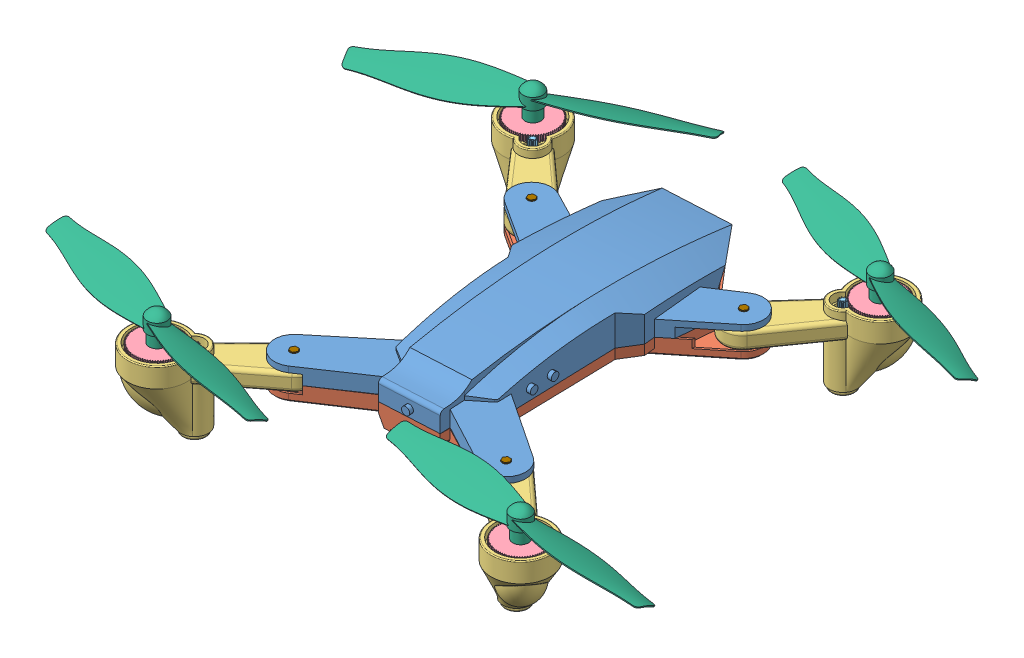
SolidWorks assembly FINALassembly, configuration Default. Lengths in mm.
Overall size (324.66 53.5 263.81).
30 component instances, 14 part files, 79 mates.
Components (placement in the parent):
- FINALtop-1: FINALtop [Default] at (85.5252 115.5284 181.2503) x (0.998665 0 -0.051658) z (0.051658 0 0.998665) size (123 19.95 170)
- FINALlower body-2: FINALlower body [Default] at (85.5252 110.5284 181.2503) x (0.998665 0 -0.051658) z (0.051658 0 0.998665) size (123 15 167)
- FINALstand-5: FINALstand [Default] at (179.7439 114.5284 292.0925) x (0.777982 0 0.628286) z (-0.628286 0 0.777982) size (75.23 38.54 30.33)
- FINALstand-6: FINALstand [Default] at (-2.951 114.5284 103.1371) x (-0.700616 0 -0.713538) z (0.713538 0 -0.700616) size (75.23 38.54 30.33)
- FINALstand-7: FINALstand [Default] at (0.9617 114.5284 298.7646) x (-0.75513 0 0.655575) z (-0.655575 0 -0.75513) size (75.23 38.54 30.33)
- FINALstand-8: FINALstand [Default] at (165.4696 114.5284 94.4251) x (0.623255 0 -0.782019) z (0.782019 0 0.623255) size (75.23 38.54 30.33)
- FINALroter part 1-1: FINALroter part 1 [Default] at (179.7439 104.0284 292.0925) x (0.103425 0 -0.994637) z (0.994637 0 0.103425) size (24 29 23.99)
- FINALroter part 2-1: FINALroter part 2 [Default] at (169.2412 98.5284 283.6107) x (-0.833907 0 0.551904) z (-0.551904 0 -0.833907) size (8 26.1 8)
- FINALroter part 1-2: FINALroter part 1 [Default] at (0.9617 104.5284 298.7646) x (0.963475 0 -0.267798) z (0.267798 0 0.963475) size (24 29 23.99)
- FINALroter part 1-3: FINALroter part 1 [Default] at (-2.951 104.5284 103.1371) x (-0.571485 0 0.820612) z (-0.820612 0 -0.571485) size (24 29 23.99)
- FINALroter part 1-4: FINALroter part 1 [Default] at (165.4696 104.5284 94.4251) x (-0.981624 0 0.190825) z (-0.190825 0 -0.981624) size (24 29 23.99)
- FINALroter part 2-2: FINALroter part 2 [Default] at (157.0556 98.5284 104.9824) x (-0.900487 0 0.434883) z (-0.434883 0 -0.900487) size (8 26.1 8)
- FINALroter part 2-3: FINALroter part 2 [Default] at (6.5073 98.5284 112.7698) x (0.010107 0 0.999949) z (-0.999949 0 0.010107) size (8 26.1 8)
- FINALroter part 2-4: FINALroter part 2 [Default] at (11.156 98.5284 289.9144) x (0.669232 0 0.743054) z (-0.743054 0 0.669232) size (8 26.1 8)
- FINALpropeller-1: FINALpropeller [Default] at (-2.951 124.5284 103.1371) x (0.424928 0 0.905227) z (-0.905227 0 0.424928) size (18.79 15 144.23)
- FINALpropeller-2: FINALpropeller [Default] at (0.9617 124.5284 298.7646) x (-0.249818 0 0.968293) z (-0.968293 0 -0.249818) size (18.79 15 144.23)
- FINALpropeller-3: FINALpropeller [Default] at (179.7439 124.0284 292.0925) x (0.103425 0 -0.994637) z (0.994637 0 0.103425) size (18.79 15 144.23)
- FINALpropeller-4: FINALpropeller [Default] at (165.4696 124.5284 94.4251) x (0.325552 0 -0.945524) z (0.945524 0 0.325552) size (18.79 15 144.23)
- FINALcamera-1: FINALcamera [Default] at (82.4538 106.2974 121.8727) x (0.998665 0 -0.051658) z (0.049898 0.258819 0.964636) size (21 11 14.8)
- FINALbush of gun-2: FINALbush of gun [Default] at (84.398 100.5284 159.46) size (8 2 8)
- FINALbolt-1: FINALbolt [Default] at (141.2182 124.0284 260.9798) x (-0.017216 0 0.999852) z (0.999852 0 0.017216) size (4 12.5 4)
- FINALbolt-2: FINALbolt [Default] at (134.606 124.0284 133.1507) x (-0.017216 0 0.999852) z (0.999852 0 0.017216) size (4 12.5 4)
- FINALbolt-3: FINALbolt [Default] at (31.7435 124.0284 138.4715) x (-0.017216 0 0.999852) z (0.999852 0 0.017216) size (4 12.5 4)
- FINALbolt-4: FINALbolt [Default] at (38.3558 124.0284 266.3006) x (-0.017216 0 0.999852) z (0.999852 0 0.017216) size (4 12.5 4)
- FINALcover-1: FINALcover [Default] at (85.0978 106.5284 159.243) x (0.998665 0 -0.051658) z (-0.051658 0 -0.998665) (suppressed, hidden)
- FINALlower motherboard-2: FINALlower motherboard [Default] at (86.1308 106.5284 150.1776) x (0.998665 0 -0.051658) z (0.051658 0 0.998665) (suppressed, hidden)
- FINALupper cover-1: FINALupper cover [Default] at (85.7105 107.5284 179.7387) x (0.998665 0 -0.051658) z (-0.051658 0 -0.998665) (suppressed, hidden)
- FINALupper motherboard-2: FINALupper motherboard [Default] at (86.2827 104.5284 199.2352) x (0.051658 0 0.998665) z (-0.998665 0 0.051658) (suppressed, hidden)
- FINALupper mb 2-1: FINALupper mb 2 [Default] at (87.6851 104.5284 226.1988) x (0.998665 0 -0.051658) z (0.051658 0 0.998665) (suppressed, hidden)
- FINALgun final-1: FINALgun final [Default] at (85.0965 67.6861 127.2387) x (-0.021673 0 0.999765) z (-0.999765 0 -0.021673) (suppressed, hidden)
Mates (geometry in assembly coordinates):
- Coincident8: coincident anti-aligned: plane of top-1 through (85.5252 115.5284 181.2503) normal (0 -1 0); plane of lower body-2 through (85.5252 115.5284 181.2503) normal (0 1 0)
- Coincident9: coincident aligned: plane of top-1 through (74.5487 134.5284 259.4217) normal (0.051658 0 0.998665); plane of lower body-2 through (74.5487 115.5284 259.4217) normal (0.051658 0 0.998665)
- Coincident12: coincident anti-aligned: plane of top-1 through (85.5252 115.5284 181.2503) normal (0 -1 0); plane of lower body-2 through (85.5252 115.5284 181.2503) normal (0 1 0)
- Width1: width anti-aligned: plane of top-1 through (63.7786 134.5284 239.9521) normal (-0.99742 0 0.071782); plane of lower body-2 through (113.2125 134.5284 237.395) normal (0.999503 0 -0.031513); plane of top-1 through (112.7132 115.5284 237.4208) normal (0.999725 0 -0.023461); plane of lower body-2 through (64.2779 115.5284 239.9263) normal (-0.99681 0 0.079814)
- Concentric2: concentric anti-aligned: cylinder of lower body-2 through (141.2182 112.5284 260.9798) axis (0 -1 0) radius 2; cylinder of stand-5 through (141.2182 110.5284 260.9798) axis (0 1 0) radius 2
- Coincident13: coincident anti-aligned: plane of top-1 through (141.2182 120.5284 260.9798) normal (0 -1 0); plane of stand-5 through (140.8448 120.5284 260.6782) normal (0 1 0)
- Concentric3: concentric anti-aligned: cylinder of lower body-2 through (134.606 112.5284 133.1507) axis (0 -1 0) radius 2; cylinder of stand-8 through (134.606 110.5284 133.1507) axis (0 1 0) radius 2
- Coincident14: coincident anti-aligned: plane of top-1 through (134.606 120.5284 133.1507) normal (0 -1 0); plane of stand-8 through (134.3068 120.5284 133.5261) normal (0 1 0)
- Coincident16: coincident anti-aligned: cylinder of lower body-2 through (38.3558 112.5284 266.3006) axis (0 -1 0) radius 2; circle of stand-7
- Coincident17: coincident anti-aligned: plane of top-1 through (38.3558 120.5284 266.3006) normal (0 -1 0); plane of stand-7 through (38.7182 120.5284 265.9859) normal (0 1 0)
- Coincident20: coincident anti-aligned: cylinder of lower body-2 through (31.7435 112.5284 138.4715) axis (0 -1 0) radius 2; circle of stand-6
- Coincident21: coincident anti-aligned: plane of lower body-2 through (31.7435 111.5284 138.4715) normal (0 1 0); plane of stand-6 through (32.0798 111.5284 138.814) normal (0 -1 0)
- LimitAngle2: limit planar angle = 2.617994 rad anti-aligned: plane of stand-8 through (142.4869 111.5284 139.2782) normal (0.818005 0 0.575211); plane of lower body-2 through (122.2662 111.5284 155.9292) normal (0.996019 0 0.089145)
- LimitAngle3: limit planar angle = 2.516501 rad anti-aligned: plane of lower body-2 through (126.0555 111.5284 238.8642) normal (0.978791 0 -0.20486); plane of stand-5 through (147.5831 111.5284 253.2894) normal (0.673833 0 -0.738883)
- LimitAngle4: limit planar angle = 2.617994 rad anti-aligned: plane of stand-6 through (24.5369 111.5284 145.3794) normal (-0.75429 0 0.656542); plane of lower body-2 through (46.3677 111.5284 159.8552) normal (-0.981505 0 0.191437)
- LimitAngle6: limit planar angle = 2.448734 rad anti-aligned: plane of lower body-2 through (51.1557 111.5284 242.7385) normal (-0.994705 0 -0.102776); plane of stand-7 through (31.7212 111.5284 258.8415) normal (-0.699702 0 -0.714435)
- Coincident22: coincident anti-aligned: plane of stand-5 through (169.2412 98.5284 283.6107) normal (0 1 0); plane of roter part 2-1 through (169.2412 98.5284 283.6107) normal (0 -1 0)
- Concentric4: concentric anti-aligned: cylinder of stand-5 through (169.2412 98.5284 283.6107) axis (0 1 0) radius 4; cylinder of roter part 2-1 through (169.2412 98.5284 283.6107) axis (0 -1 0) radius 4
- Coincident23: coincident aligned: plane of stand-5 through (179.7439 104.5284 292.0925) normal (0 1 0); circle of roter part 1-1
- Concentric5: concentric anti-aligned: cylinder of stand-5 through (179.7439 104.5284 292.0925) axis (0 1 0) radius 3; cylinder of roter part 1-1 through (179.7439 104.0284 292.0925) axis (0 -1 0) radius 3
- Coincident24: coincident anti-aligned: plane of stand-7 through (11.156 98.5284 289.9144) normal (0 1 0); circle of roter part 2-4
- Concentric6: concentric anti-aligned: cylinder of stand-7 through (11.156 98.5284 289.9144) axis (0 1 0) radius 4; cylinder of roter part 2-4 through (11.156 98.5284 289.9144) axis (0 -1 0) radius 4
- Coincident25: coincident anti-aligned: plane of stand-7 through (0.9617 104.5284 298.7646) normal (0 1 0); circle of roter part 1-2
- Concentric7: concentric anti-aligned: cylinder of stand-7 through (0.9617 104.5284 298.7646) axis (0 1 0) radius 3; cylinder of roter part 1-2 through (0.9617 104.5284 298.7646) axis (0 -1 0) radius 3
- Coincident31: coincident anti-aligned: plane of stand-6 through (6.5073 98.5284 112.7698) normal (0 1 0); plane of roter part 2-3 through (6.5073 98.5284 112.7698) normal (0 -1 0)
- Concentric13: concentric anti-aligned: cylinder of stand-6 through (6.5073 98.5284 112.7698) axis (0 1 0) radius 4; cylinder of roter part 2-3 through (6.5073 98.5284 112.7698) axis (0 -1 0) radius 4
- Coincident32: coincident anti-aligned: plane of stand-6 through (-2.951 104.5284 103.1371) normal (0 1 0); plane of roter part 1-3 through (-2.951 104.5284 103.1371) normal (0 -1 0)
- Concentric14: concentric anti-aligned: cylinder of stand-6 through (-2.951 104.5284 103.1371) axis (0 1 0) radius 3; cylinder of roter part 1-3 through (-2.951 104.5284 103.1371) axis (0 -1 0) radius 3
- Coincident33: coincident anti-aligned: plane of stand-8 through (157.0556 98.5284 104.9824) normal (0 1 0); plane of roter part 2-2 through (157.0556 98.5284 104.9824) normal (0 -1 0)
- Concentric15: concentric anti-aligned: cylinder of stand-8 through (157.0556 98.5284 104.9824) axis (0 1 0) radius 4; cylinder of roter part 2-2 through (157.0556 98.5284 104.9824) axis (0 -1 0) radius 4
- Coincident34: coincident anti-aligned: plane of stand-8 through (165.4696 104.5284 94.4251) normal (0 1 0); plane of roter part 1-4 through (165.4696 104.5284 94.4251) normal (0 -1 0)
- Concentric16: concentric anti-aligned: cylinder of stand-8 through (165.4696 104.5284 94.4251) axis (0 1 0) radius 3; cylinder of roter part 1-4 through (165.4696 104.5284 94.4251) axis (0 -1 0) radius 3
- GearMate2: gear = 75 : 11 mm: cylinder of FINALroter part 1-3 through (-2.951 104.5284 103.1371) axis (0 -1 0) radius 3; cylinder of FINALroter part 2-3 through (6.5073 98.5284 112.7698) axis (0 -1 0) radius 4
- GearMate3: gear = 75 : 11 mm: cylinder of FINALroter part 1-2 through (0.9617 104.5284 298.7646) axis (0 -1 0) radius 3; cylinder of FINALroter part 2-4 through (11.156 98.5284 289.9144) axis (0 -1 0) radius 4
- GearMate4: gear = 75 : 11 mm: cylinder of FINALroter part 2-1 through (169.2412 98.5284 283.6107) axis (0 -1 0) radius 4; cylinder of FINALroter part 1-1 through (179.7439 104.0284 292.0925) axis (0 -1 0) radius 3
- GearMate5: gear = 75 : 11 mm: cylinder of FINALroter part 2-2 through (157.0556 98.5284 104.9824) axis (0 -1 0) radius 4; cylinder of FINALroter part 1-4 through (165.4696 104.5284 94.4251) axis (0 -1 0) radius 3
- Coincident44: coincident anti-aligned: plane of roter part 1-3 through (-4.6007 124.5284 105.506) normal (-0.084615 0 0.996414); plane of propeller-1 through (-1.7243 131.5284 105.7502) normal (0.084615 0 -0.996414)
- Coincident45: coincident anti-aligned: plane of roter part 1-3 through (-0.0746 124.5284 103.3813) normal (0.905227 0 -0.424928); plane of propeller-1 through (-1.3013 131.5284 100.7682) normal (-0.905227 0 0.424928)
- Parallel2: parallel anti-aligned: plane of roter part 1-3 through (-9.8088 124.5284 112.9844) normal (0 1 0); plane of propeller-1 through (-2.951 124.5284 103.1371) normal (0 -1 0)
- Coincident47: coincident anti-aligned: plane of roter part 1-3 through (-9.8088 124.5284 112.9844) normal (0 1 0); plane of propeller-1 through (-2.951 124.5284 103.1371) normal (0 -1 0)
- Coincident51: coincident anti-aligned: plane of roter part 1-2 through (0.2405 124.5284 301.5599) normal (0.267798 0 0.963475); plane of propeller-2 through (3.0219 131.5284 300.7868) normal (-0.267798 0 -0.963475)
- Coincident52: coincident anti-aligned: plane of roter part 1-2 through (3.0219 124.5284 300.7868) normal (0.968293 0 0.249818); plane of propeller-2 through (3.743 131.5284 297.9916) normal (-0.968293 0 -0.249818)
- Coincident53: coincident aligned: plane of roter part 1-2 through (12.5234 124.5284 295.5511) normal (0 1 0); circle of propeller-2
- Coincident56: coincident anti-aligned: plane of roter part 1-1 through (179.4453 124.0284 294.9638) normal (0.40775 0 0.913094); plane of propeller-3 through (182.0812 131.0284 293.7867) normal (-0.40775 0 -0.913094)
- Coincident57: coincident anti-aligned: plane of roter part 1-1 through (182.0812 124.0284 293.7867) normal (0.994637 0 0.103425); plane of propeller-3 through (182.3798 131.0284 290.9155) normal (-0.994637 0 -0.103425)
- Coincident58: coincident anti-aligned: plane of roter part 1-1 through (180.985 124.0284 280.1569) normal (0 1 0); plane of propeller-3 through (179.7439 124.0284 292.0925) normal (0 -1 0)
- Coincident59: coincident anti-aligned: plane of roter part 1-4 through (166.4094 124.5284 91.6956) normal (-0.190825 0 -0.981624); plane of propeller-4 through (163.5757 131.5284 92.2465) normal (0.190825 0 0.981624)
- Coincident60: coincident anti-aligned: plane of roter part 1-4 through (163.5757 124.5284 92.2465) normal (-0.945524 0 -0.325552); plane of propeller-4 through (162.6359 131.5284 94.976) normal (0.945524 0 0.325552)
- Coincident61: coincident anti-aligned: plane of roter part 1-4 through (153.6901 124.5284 96.715) normal (0 1 0); plane of propeller-4 through (165.4696 124.5284 94.4251) normal (0 -1 0)
- Concentric17: concentric anti-aligned: cylinder of lower body-2 through (71.9397 102.5284 121.8728) axis (0.998665 0 -0.051658) radius 0.75; cylinder of camera-1 through (92.9117 102.5284 120.788) axis (-0.998665 0 0.051658) radius 0.75
- Concentric18: concentric anti-aligned: cylinder of lower body-2 through (71.9397 102.5284 121.8728) axis (0.998665 0 -0.051658) radius 0.75; cylinder of camera-1 through (92.9117 102.5284 120.788) axis (-0.998665 0 0.051658) radius 0.75
- Coincident62: coincident anti-aligned: plane of lower body-2 through (91.7408 112.2684 122.3506) normal (-0.998665 0 0.051658); plane of camera-1 through (91.4682 110.8335 117.0794) normal (0.998665 0 -0.051658)
- LimitAngle7: limit planar angle = 2.879793 rad aligned: plane of camera-1 through (82.3802 111.61 120.4511) normal (-0.01337 0.965926 -0.258473); plane of lower body-2 through (91.7408 112.2684 122.3506) normal (0 -1 0)
- Concentric21: concentric aligned: cylinder of lower body-2 through (84.398 115.5284 159.46) axis (0 -1 0) radius 4; cylinder of bush of gun-2 through (84.398 102.5284 159.46) axis (0 -1 0) radius 4
- Coincident69: coincident aligned: plane of lower body-2 through (94.7024 100.5284 116.6901) normal (0 -1 0); plane of bush of gun-2 through (84.398 100.5284 159.46) normal (0 -1 0)
- Concentric23: concentric aligned: cylinder of top-1 through (141.2182 119.5284 260.9798) axis (0 1 0) radius 1; cylinder of bolt-1 through (141.2182 111.5284 260.9798) axis (0 1 0) radius 1
- Coincident74: coincident anti-aligned: plane of top-1 through (141.2182 121.5284 260.9798) normal (0 1 0); plane of bolt-1 through (141.2182 121.5284 260.9798) normal (0 -1 0)
- Concentric25: concentric aligned: cylinder of top-1 through (134.606 119.5284 133.1507) axis (0 1 0) radius 1; cylinder of bolt-2 through (134.606 111.5284 133.1507) axis (0 1 0) radius 1
- Coincident75: coincident anti-aligned: plane of top-1 through (134.606 121.5284 133.1507) normal (0 1 0); circle of bolt-2
- Concentric26: concentric aligned: cylinder of top-1 through (38.3558 119.5284 266.3006) axis (0 1 0) radius 1; cylinder of bolt-4 through (38.3558 111.5284 266.3006) axis (0 1 0) radius 1
- Coincident76: coincident anti-aligned: plane of top-1 through (38.3558 121.5284 266.3006) normal (0 1 0); plane of bolt-4 through (38.3558 121.5284 266.3006) normal (0 -1 0)
- Concentric27: concentric aligned: cylinder of top-1 through (31.7435 119.5284 138.4715) axis (0 1 0) radius 1; cylinder of bolt-3 through (31.7435 111.5284 138.4715) axis (0 1 0) radius 1
- Coincident77: coincident anti-aligned: plane of top-1 through (31.7435 121.5284 138.4715) normal (0 1 0); plane of bolt-3 through (31.7435 121.5284 138.4715) normal (0 -1 0)
- Coincident81: coincident anti-aligned: plane of FINALlower body-2 through (94.7024 101.5284 116.6901) normal (0 1 0); plane of FINALcover-1 through (85.0978 101.5284 159.243) normal (0 -1 0)
- Coincident82: coincident anti-aligned: plane of FINALlower body-2 through (96.2209 110.5284 180.6971) normal (-0.998665 0 0.051658); plane of FINALcover-1 through (93.8705 101.5284 135.2578) normal (0.998665 0 -0.051658)
- Coincident83: coincident anti-aligned: plane of FINALlower body-2 through (56.1248 100.5284 174.2598) normal (-0.051658 0 -0.998665); plane of FINALcover-1 through (75.8085 101.5284 173.2416) normal (0.051658 0 0.998665)
- Coincident84: coincident: plane of FINALcover-1 through (85.0978 106.5284 159.243) normal (0 1 0); plane of FINALlower motherboard-2 through (86.1308 106.5284 150.1776) normal (0 -1 0)
- Coincident85: coincident anti-aligned: plane of FINALlower body-2 through (56.1248 100.5284 174.2598) normal (-0.051658 0 -0.998665); plane of FINALlower motherboard-2 through (78.8045 107.5284 173.0866) normal (0.051658 0 0.998665)
- Coincident86: coincident anti-aligned: plane of FINALlower body-2 through (96.2209 110.5284 180.6971) normal (-0.998665 0 0.051658); plane of FINALlower motherboard-2 through (93.4572 107.5284 127.2685) normal (0.998665 0 -0.051658)
- Coincident87: coincident anti-aligned: plane of FINALlower body-2 through (56.1765 104.5284 175.2584) normal (0 1 0); plane of FINALupper cover-1 through (85.7105 104.5284 179.7387) normal (0 -1 0)
- Coincident88: coincident: plane of FINALlower motherboard-2 through (78.8045 107.5284 173.0866) normal (0.051658 0 0.998665); plane of FINALupper cover-1 through (75.3622 104.5284 173.2647) normal (-0.051658 0 -0.998665)
- Coincident89: coincident anti-aligned: plane of FINALlower body-2 through (56.1765 104.5284 175.2584) normal (0 1 0); plane of FINALupper motherboard-2 through (86.2827 104.5284 199.2352) normal (0 -1 0)
- Coincident90: coincident: plane of FINALupper cover-1 through (76.0855 104.5284 187.246) normal (0.051658 0 0.998665); plane of FINALupper motherboard-2 through (78.1469 106.0284 187.1393) normal (-0.051658 0 -0.998665)
- Lock1: lock: unknown of FINALlower body-2; unknown of FINALupper motherboard-2
- Coincident91: coincident: plane of FINALupper motherboard-2 through (79.4384 106.0284 212.106) normal (0.051658 0 0.998665); plane of FINALupper mb 2-1 through (76.9494 106.5284 212.2347) normal (-0.051658 0 -0.998665)
- Coincident92: coincident anti-aligned: plane of FINALlower body-2 through (56.1765 104.5284 175.2584) normal (0 1 0); plane of FINALupper mb 2-1 through (87.6851 104.5284 226.1988) normal (0 -1 0)
- Lock2: lock: unknown of FINALlower body-2; unknown of FINALupper mb 2-1
- Concentric28: concentric anti-aligned: cylinder of FINALbush of gun-2 through (84.398 102.5284 159.46) axis (0 -1 0) radius 3; cylinder of ? through (84.398 -499906.9716 159.46) axis (0 1 0) radius 2.75
- Coincident93: coincident aligned: circle of FINALbush of gun-2; plane of ? through (84.398 102.5284 159.46) normal (0 1 0)
